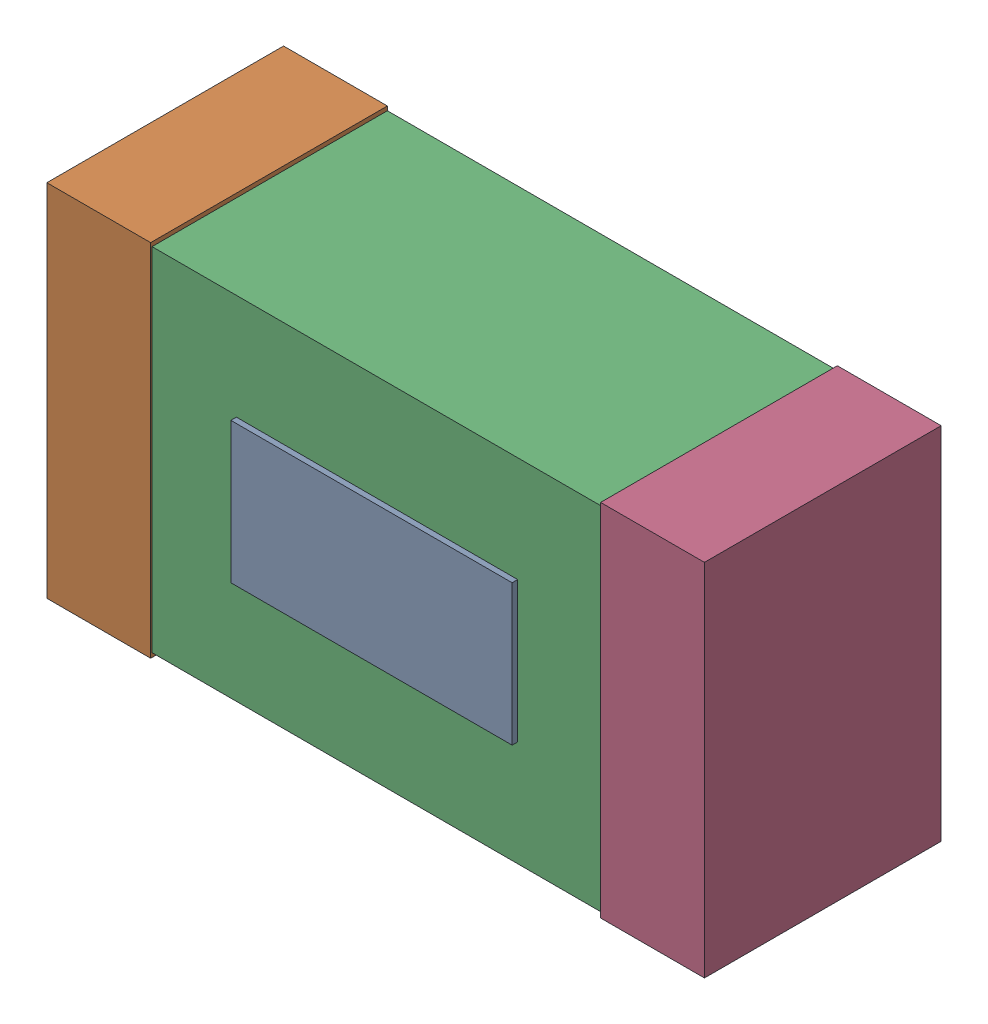
SolidWorks assembly D4, configuration Default. Lengths in mm.
Overall size (2.38 1.3 0.87).
8 component instances, 3 part files, 0 mates.
Components (placement in the parent):
- 384311488-1: 384311488 [Default] at (6.35 73.152 0) size (1.02 0.51 0.87)
  - Extruded_15-1: Extruded_15 [Default] at origin size (1.02 0.51 0.87)
- 384311232-1: 384311232 [Default] at (5.35 73.152 0) size (0.38 1.3 0.85)
  - Extruded_8-1: Extruded_8 [Default] at origin size (0.38 1.3 0.85)
- 384311360-1: 384311360 [Default] at (6.35 73.152 0) size (2.2 1.27 0.85)
  - Extruded_9-1: Extruded_9 [Default] at origin size (2.2 1.27 0.85)
- 384311232-2: 384311232 [Default] at (7.35 73.152 0) size (0.38 1.3 0.85)
  - Extruded_8-1: Extruded_8 [Default] at origin size (0.38 1.3 0.85)
